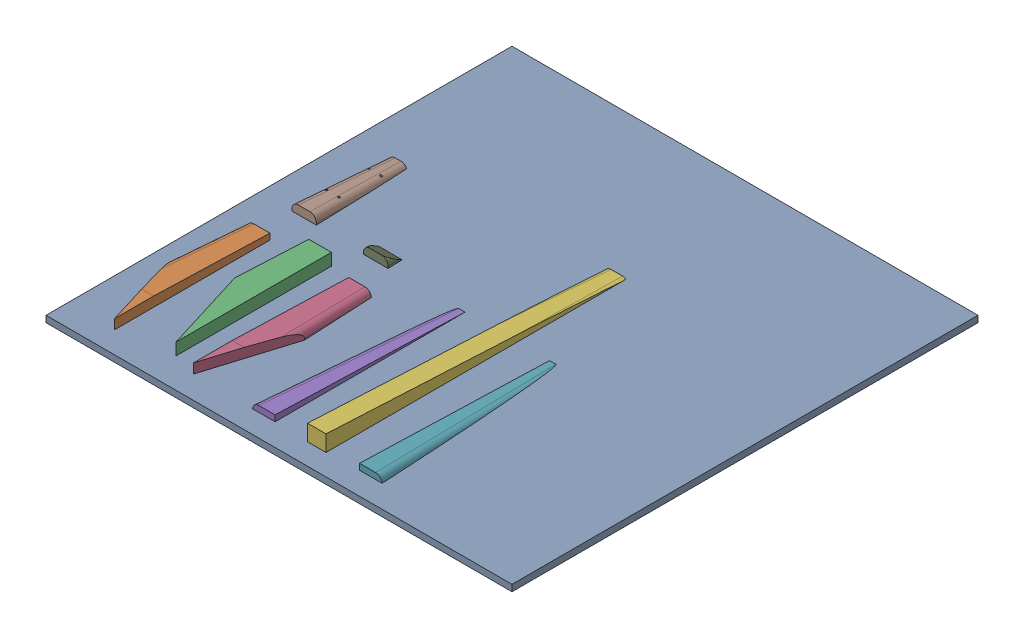
SolidWorks assembly Fuselage Mold_Operation 2, configuration Default. Lengths in mm.
Overall size (574.61 44.3 591.67).
9 component instances, 9 part files, 9 mates.
Components (placement in the parent):
- Cut Area-1: Cut Area [Default] at origin size (914.4 12.7 914.4) (hidden)
- Fuselage Mold-Bottom-FrontRight-1: Fuselage Mold-Bottom-FrontRight [Default] at (86.017 -18.161 236.7456) x (0 -1 0) z (0 0 1) size (31.75 51.29 304.8)
- Fuselage Mold-Bottom-FrontMiddle-1: Fuselage Mold-Bottom-FrontMiddle [Default] at (190.6494 18.161 220.8508) x (0 -1 0) z (0 0 1) size (36.32 51.29 304.8)
- Fuselage Mold-Bottom-FrontLeft-1: Fuselage Mold-Bottom-FrontLeft [Default] at (250.6096 -18.161 234.7006) x (0 1 0) z (0 0 1) size (31.75 51.29 304.8)
- Fuselage Mold-Bottom-BackRight-1: Fuselage Mold-Bottom-BackRight [Default] at (399.8449 -18.161 540.455) x (0 -1 0) z (0 0 1) size (24.51 44.29 588.97)
- Fuselage Mold-Bottom-BackMiddle-1: Fuselage Mold-Bottom-BackMiddle [Default] at (489.687 5.969 542.6473) x (-1 0 0) z (0 0 1) size (36.32 44.29 588.97)
- Fuselage Mold-Bottom-BackLeft-1: Fuselage Mold-Bottom-BackLeft [Default] at (576.9807 -18.161 539.9491) x (0 1 0) z (0 0 1) size (24.51 44.29 588.97)
- TailMountMold-Bottom-2: TailMountMold-Bottom [Default] at (87.9803 20.7232 754.7258) x (-1 0 0) z (0 0 1) size (48.01 29.19 184.48)
- TailMountMold-Top-1: TailMountMold-Top [Default] at (232.0538 -20.7232 758.0428) size (48.01 29.19 184.48)
Mates (geometry in assembly coordinates):
- Coincident1: coordinate: point of Cut Area-1
- Distance1: distance = 0 mm aligned: plane of Fuselage Mold-Bottom-FrontRight-1 through (86.017 0 236.7456) normal (0 -1 0); plane of Cut Area-1 through (0 0 0) normal (0 -1 0)
- Distance3: distance = 0 mm aligned: plane of Fuselage Mold-Bottom-FrontLeft-1 through (250.6096 0 234.7006) normal (0 -1 0); plane of Cut Area-1 through (0 0 0) normal (0 -1 0)
- Distance4: distance = 0 mm aligned: plane of Fuselage Mold-Bottom-BackRight-1 through (399.8449 0 540.455) normal (0 -1 0); plane of Cut Area-1 through (0 0 0) normal (0 -1 0)
- Distance5: distance = 0 mm aligned: plane of Fuselage Mold-Bottom-BackMiddle-1 through (489.687 0 542.6473) normal (0 -1 0); plane of Cut Area-1 through (0 0 0) normal (0 -1 0)
- Distance6: distance = 0 mm aligned: plane of Fuselage Mold-Bottom-BackLeft-1 through (576.9807 0 539.9491) normal (0 -1 0); plane of Cut Area-1 through (0 0 0) normal (0 -1 0)
- Distance7: distance = 0 mm aligned: plane of TailMountMold-Bottom-2 through (87.9803 0 754.7258) normal (0 -1 0); plane of Cut Area-1 through (0 0 0) normal (0 -1 0)
- Distance8: distance = 0 mm aligned: plane of TailMountMold-Top-1 through (232.0538 0 758.0428) normal (0 -1 0); plane of Cut Area-1 through (0 0 0) normal (0 -1 0)
- Distance9: distance = 0 mm aligned: plane of Fuselage Mold-Bottom-FrontMiddle-1 through (190.6494 0 220.8508) normal (0 -1 0); plane of Cut Area-1 through (0 0 0) normal (0 -1 0)
